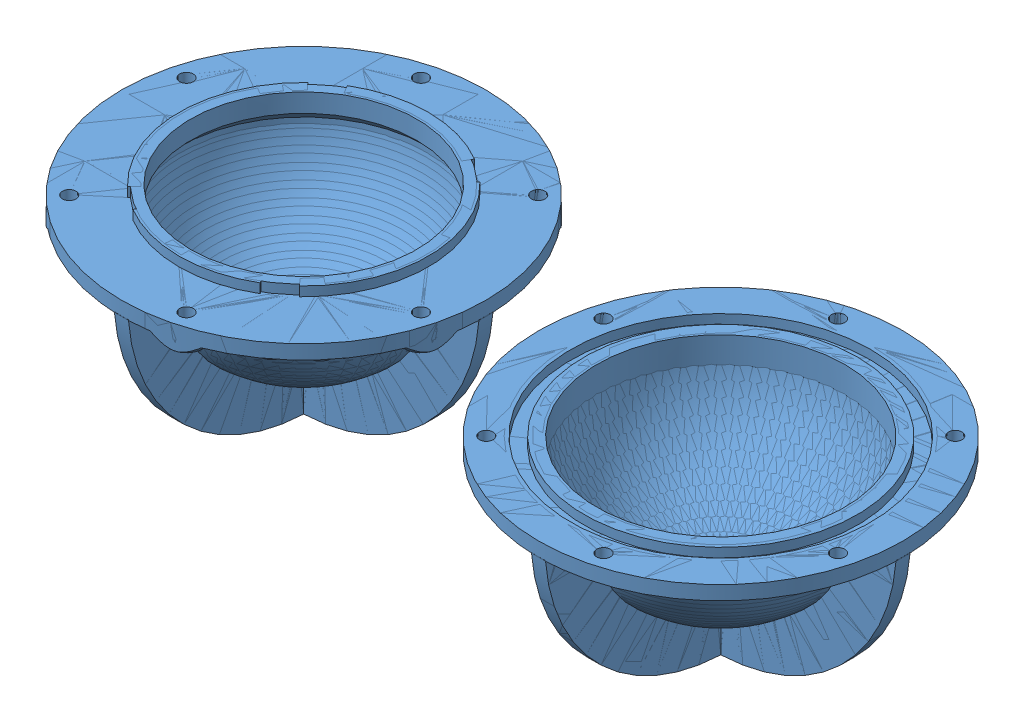
SolidWorks assembly Housing_comparison_Prototype, configuration Default. Lengths in mm.
Overall size (166.59 40.96 77.69).
4 component instances, 1 part files, 6 mates.
Components (placement in the parent):
- housing2_rev2-1: housing2_rev2 [2-140_UP] at origin size (77.69 40.96 77.69)
- housing2_rev2-2: housing2_rev2 [2-140_UP_Proto1] at origin size (77.69 40.96 77.69)
- housing2_rev2-3: housing2_rev2 [2-140] at (88.9 0 0) size (77.69 38.96 77.69)
- housing2_rev2-4: housing2_rev2 [2-140_Proto1] at (88.9 0 0) size (77.69 38.96 77.69)
Mates (geometry in assembly coordinates):
- Coincident1: coordinate: point of housing2_rev2-3; point of housing2_rev2-4
- Coincident2: coordinate: point of housing2_rev2-1; point of housing2_rev2-2
- Coincident4: coordinate: unknown of housing2_rev2-1
- Distance1: distance = 88.9 mm: unknown of housing2_rev2-3
- Coincident8: coincident aligned: plane of housing2_rev2-4 through (88.9 0 0) normal (0 1 0)
- Coincident9: coincident aligned: plane of housing2_rev2-4 through (88.9 0 0) normal (0 0 1)
